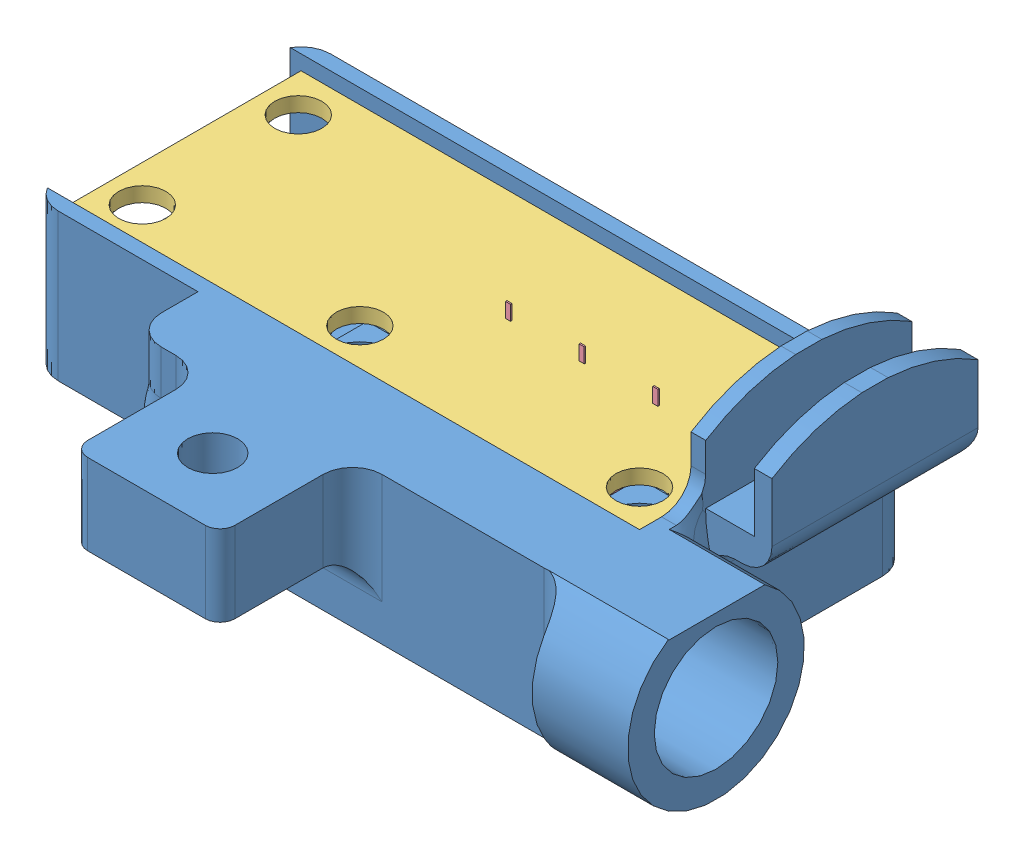
SolidWorks assembly Ensamblaje F-Sensor, configuration Predeterminado. Lengths in mm.
Overall size (48 17 32).
8 component instances, 5 part files, 3 mates.
Components (placement in the parent):
- Soporte F-Sensor-1: Soporte F-Sensor [Predeterminado] at (16.1815 -4.8501 50.75) size (48 17 32)
- Endstop Led-1: Endstop Led [Predeterminado] at (-3.5685 4.1499 41.25) x (-1 0 0) z (0 1 0) size (39.5 18.65 8)
  - Konstruktion24-1: Konstruktion24 [Predeterminado] at origin size (2.5 1.5 1)
  - Endstop-1: Endstop [Predeterminado] at origin size (39.5 18.65 8)
    - PCB-1: PCB [Predeterminado] at origin size (39.5 16 1)
      - PCB^Endstop-1: PCB^Endstop [Predeterminado] x (1 0 0) z (0 0 -1) size (39.5 16 1)
    - Microswitch_1A_125vAC(seul)-1: Microswitch_1A_125vAC(seul) [Predeterminado] at (-5.9433 8 -4) x (0 1 0) z (0 0 -1) size (11.12 16.44 8)
    - JST 4Pin-1: JST 4Pin [Predeterminado] at (10.68 0.36 -3.4) x (0 1 0) z (0 0 -1) size (12.4 8.75 6.1)
Mates (geometry in assembly coordinates):
- Coincidente1: coincident anti-aligned: plane of Soporte F-Sensor-1 through (16.1815 -2.8501 50.75) normal (0 1 0); plane of Endstop Led-1/Endstop-1/Microswitch_1A_125vAC(seul)-1 through (2.3749 -2.8501 49.25) normal (0 -1 0)
- Coincidente2: coincident anti-aligned: plane of Soporte F-Sensor-1 through (15.1815 -2.8501 33.25) normal (0 0 1); plane of Endstop Led-1/Endstop-1/PCB-1/PCB^Endstop-1 through (8.6815 3.1499 33.25) normal (0 0 -1)
- Coincidente3: coincident anti-aligned: plane of Soporte F-Sensor-1 through (15.1815 -2.8501 49.75) normal (-1 0 0); plane of Endstop Led-1/Endstop-1/PCB-1/PCB^Endstop-1 through (15.1815 3.1499 46.25) normal (1 0 0)
